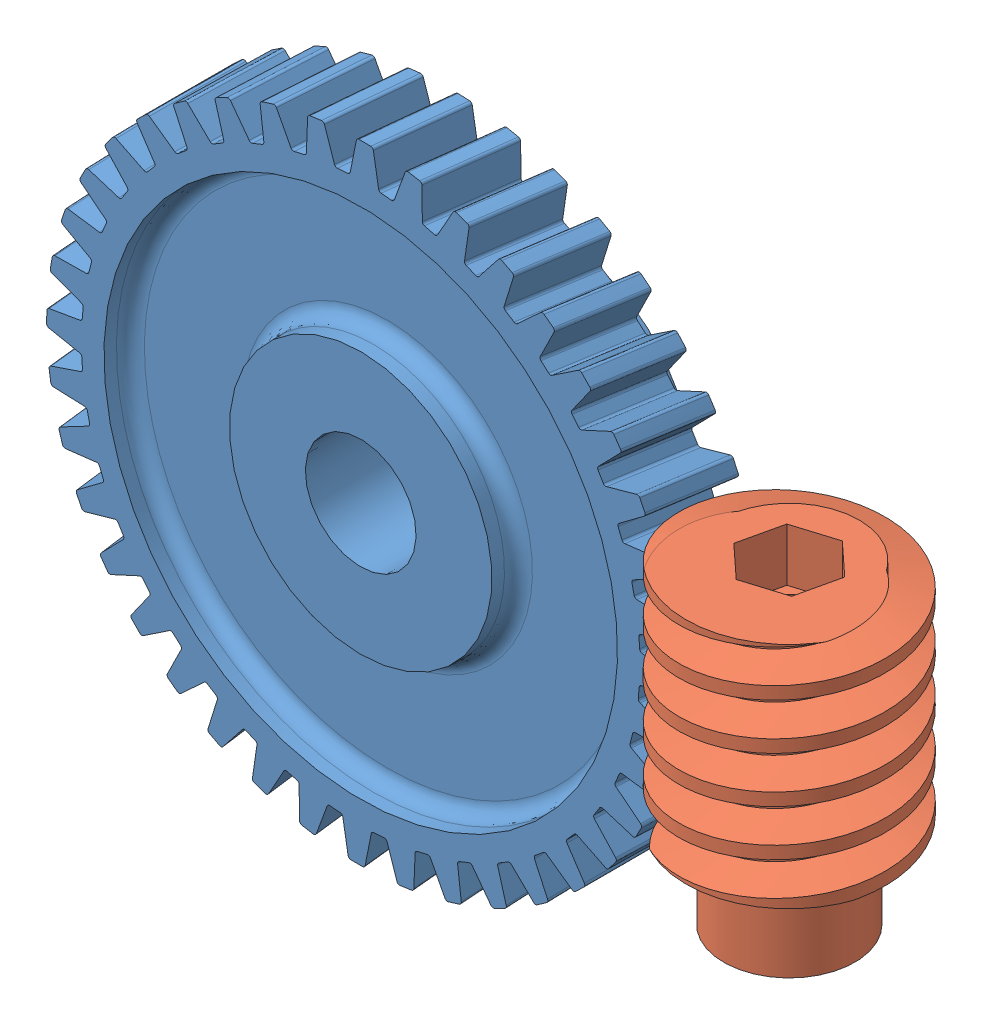
SolidWorks assembly worm and gear assembly, configuration Default. Lengths in mm.
Overall size (66.09 62.08 18.48).
2 component instances, 2 part files, 7 mates.
Components (placement in the parent):
- helical gear 40 teeth-1: helical gear 40 teeth [Default] x (0.533684 0.845684 0) z (0 0 1) size (45 45 14.2)
- worm for helical gear-1: worm for helical gear [Default] at (27.5 -14 0) x (0.010427 0 -0.999946) z (0.999946 0 0.010427) size (14.8 23.3 14.87)
Mates (geometry in assembly coordinates):
- Coincident1: coincident: line of helical gear 40 teeth-1 through (0 0 -11) axis (0 0 1); plane of assembly
- Coincident2: coincident: line of helical gear 40 teeth-1 through (0 0 -11) axis (0 0 1); plane of assembly
- Coincident3: coincident: plane of helical gear 40 teeth-1 through (0 0 0) normal (0 0 1); plane of assembly through (0 0 0) normal (0 0 1)
- Coincident4: coincident: line of worm for helical gear-1 through (27.5 12.0628 0) axis (0 -1 0); plane of assembly
- Distance1: distance = 27.5 mm: line of worm for helical gear-1 through (27.5 12.0628 0) axis (0 -1 0); plane of assembly
- Distance2: distance = 14 mm: plane of assembly through (0 0 0) normal (0 1 0); plane of worm for helical gear-1
- GearMate1: gear = 40 : 1 mm: cylinder of worm for helical gear-1 through (27.5 -19.1587 0) axis (0 -1 0) radius 4.7; cylinder of helical gear 40 teeth-1 through (0 0 0) axis (0 0 1) radius 3.9688
